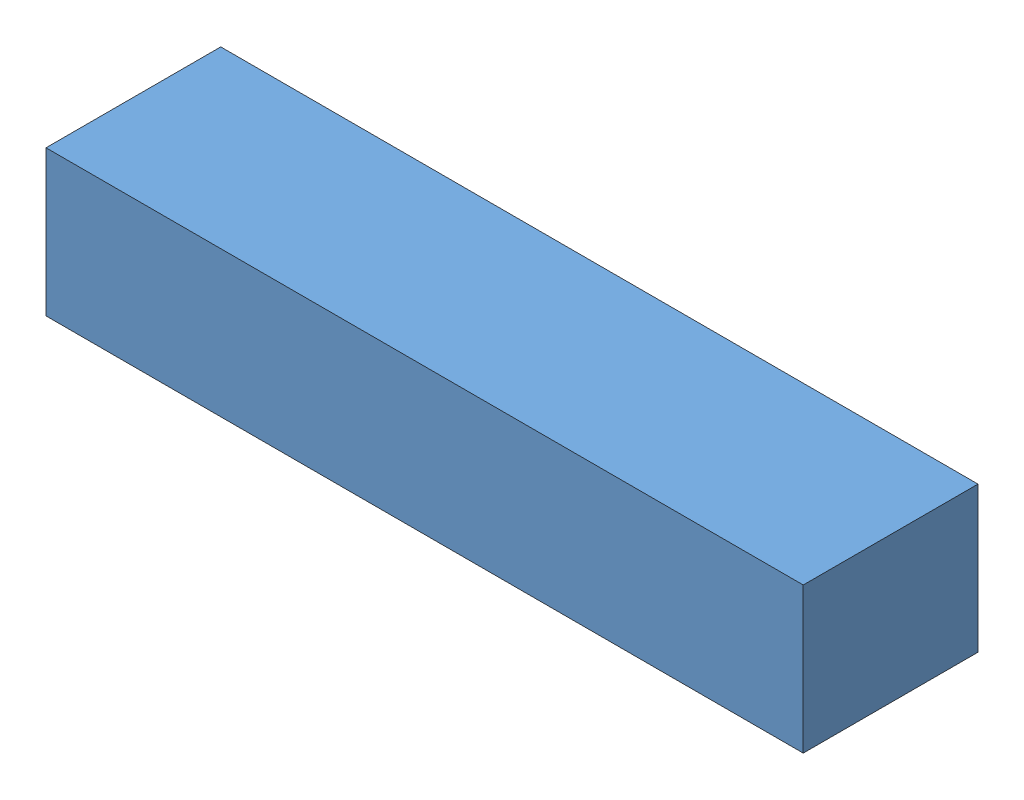
SolidWorks assembly Box and motoe, configuration Default. Lengths in mm.
Overall size (260 52.55 60).
8 component instances, 4 part files, 25 mates.
Components (placement in the parent):
- 101522-1: 101522 [Default] at origin size (260 50 60)
- holder-2: holder [Default] at (-77.2488 19.5572 50.8862) x (0 0 -1) z (1 0 0) size (25.56 40 12.5)
- holder-3: holder [Default] at (-48.3006 19.5572 50.8862) x (0 0 -1) z (1 0 0) size (25.56 40 12.5)
- holder-4: holder [Default] at (40.75 19.5572 50.8862) x (0 0 -1) z (1 0 0) size (25.56 40 12.5)
- SG90-2: SG90 [Default] at (-76.9358 7.4702 -6.8582) x (0 -1 0) z (1 0 0) size (32.36 29.6 12.25)
- SG90-4: SG90 [Default] at (-48.0006 7.4702 -6.8582) x (0 -1 0) z (1 0 0) size (32.36 29.6 12.25)
- SG90-11: SG90 [Default] at (41.05 7.4702 -6.8582) x (0 -1 0) z (1 0 0) size (32.36 29.6 12.25)
- SG90_ARM-2: SG90_ARM [Default] at (47.15 13.5702 -15.7781) x (-0.001218 0.999999 0) z (-0.999999 -0.001218 0) size (19.74 4.23 7.24)
Mates (geometry in assembly coordinates):
- Coincident6: coincident anti-aligned: plane of SG90-1 through (165.1877 127.9455 -33.5582) normal (0 0 1); plane of holder-1 through (177.6262 105.4157 -33.5582) normal (0 0 -1)
- Coincident7: coincident anti-aligned: plane of SG90-1 through (165.1877 105.4157 -33.5582) normal (0 -1 0); plane of holder-1 through (177.6262 105.4157 -50.5582) normal (0 1 0)
- Parallel2: parallel anti-aligned: plane of SG90-1 through (165.1877 127.9455 -50.3582) normal (0 1 0); plane of holder-1 through (177.6262 128.4157 -33.5582) normal (0 -1 0)
- Parallel3: parallel anti-aligned: plane of SG90-1 through (165.1877 132.8604 -50.3582) normal (0 0 1); plane of holder-1 through (177.6262 98.4157 -50.5582) normal (0 0 -1)
- Coincident10: coincident anti-aligned: plane of SG90-1 through (165.1877 105.4157 -33.5582) normal (0 -1 0); plane of holder-1 through (177.6262 105.4157 -50.5582) normal (0 1 0)
- Parallel4: parallel anti-aligned: plane of SG90-1 through (165.1877 127.9455 -50.3582) normal (0 1 0); plane of holder-1 through (177.6262 128.4157 -33.5582) normal (0 -1 0)
- Coincident13: coincident aligned: plane of 101522-1 through (125 304.951 -25) normal (0 0 1); plane of holder-1 through (177.6262 138.4157 -25) normal (0 0 1)
- Coincident15: coincident anti-aligned: plane of 101522-1 through (125 304.951 25) normal (0 0 -1); plane of holder-2 through (-64.7488 40 25) normal (0 0 1)
- Coincident16: coincident anti-aligned: plane of 101522-1 through (0 40 0) normal (0 -1 0); plane of holder-2 through (-64.7488 40 -0.5582) normal (0 1 0)
- Coincident20: coincident anti-aligned: plane of 101522-1 through (125 304.951 25) normal (0 0 -1); plane of holder-3 through (-35.8006 40 25) normal (0 0 1)
- Coincident24: coincident anti-aligned: plane of 101522-1 through (0 40 0) normal (0 -1 0); plane of holder-3
- Coincident25: coincident anti-aligned: plane of 101522-1 through (125 304.951 25) normal (0 0 -1); plane of holder-4 through (53.25 40 25) normal (0 0 1)
- Coincident26: coincident anti-aligned: plane of 101522-1 through (0 40 0) normal (0 -1 0); plane of holder-4 through (53.25 40 -0.5582) normal (0 1 0)
- Coincident41: coincident anti-aligned: plane of holder-2 through (-64.7488 7 16.4418) normal (0 0 -1); plane of SG90-2 through (-64.7358 7.4702 16.4418) normal (0 0 1)
- Coincident42: coincident anti-aligned: plane of holder-2 through (-64.7488 30 16.4418) normal (0 -1 0); plane of SG90-2 through (-64.7358 30 16.4418) normal (0 1 0)
- Coincident45: coincident anti-aligned: plane of holder-3 through (-35.8006 7 16.4418) normal (0 0 -1); plane of SG90-4 through (-35.8006 7.4702 16.4418) normal (0 0 1)
- Coincident46: coincident anti-aligned: plane of holder-3; plane of SG90-4
- Coincident47: coincident aligned: plane of holder-3; plane of SG90-4
- Coincident55: coincident anti-aligned: plane of holder-4 through (53.25 7 16.4418) normal (0 0 -1); plane of SG90-11 through (53.25 7.4702 16.4418) normal (0 0 1)
- Coincident56: coincident anti-aligned: plane of holder-4 through (53.25 30 16.4418) normal (0 -1 0); plane of SG90-11 through (53.25 30 16.4418) normal (0 1 0)
- Coincident57: coincident aligned: plane of holder-4 through (53.25 19.5572 50.8862) normal (1 0 0); plane of SG90-11 through (53.25 7.4702 -6.8582) normal (1 0 0)
- Coincident59: coincident anti-aligned: plane of SG90-11 through (53.25 7.4702 -13.1619) normal (0 0 -1); plane of SG90_ARM-2 through (47.15 13.5702 -13.1619) normal (0 0 1)
- Parallel9: parallel anti-aligned: plane of SG90-11 through (53.25 7.4702 -13.1619) normal (0 0 -1); plane of SG90_ARM-2 through (47.15 13.5702 -15.4987) normal (0 0 1)
- Concentric3: concentric anti-aligned: circle of SG90-11; circle of SG90_ARM-2
- Distance2: distance = 165.75 mm anti-aligned: plane of holder-4 through (40.75 19.5572 50.8862) normal (-1 0 0); plane of 101522-1 through (-125 304.951 -25) normal (1 0 0)
